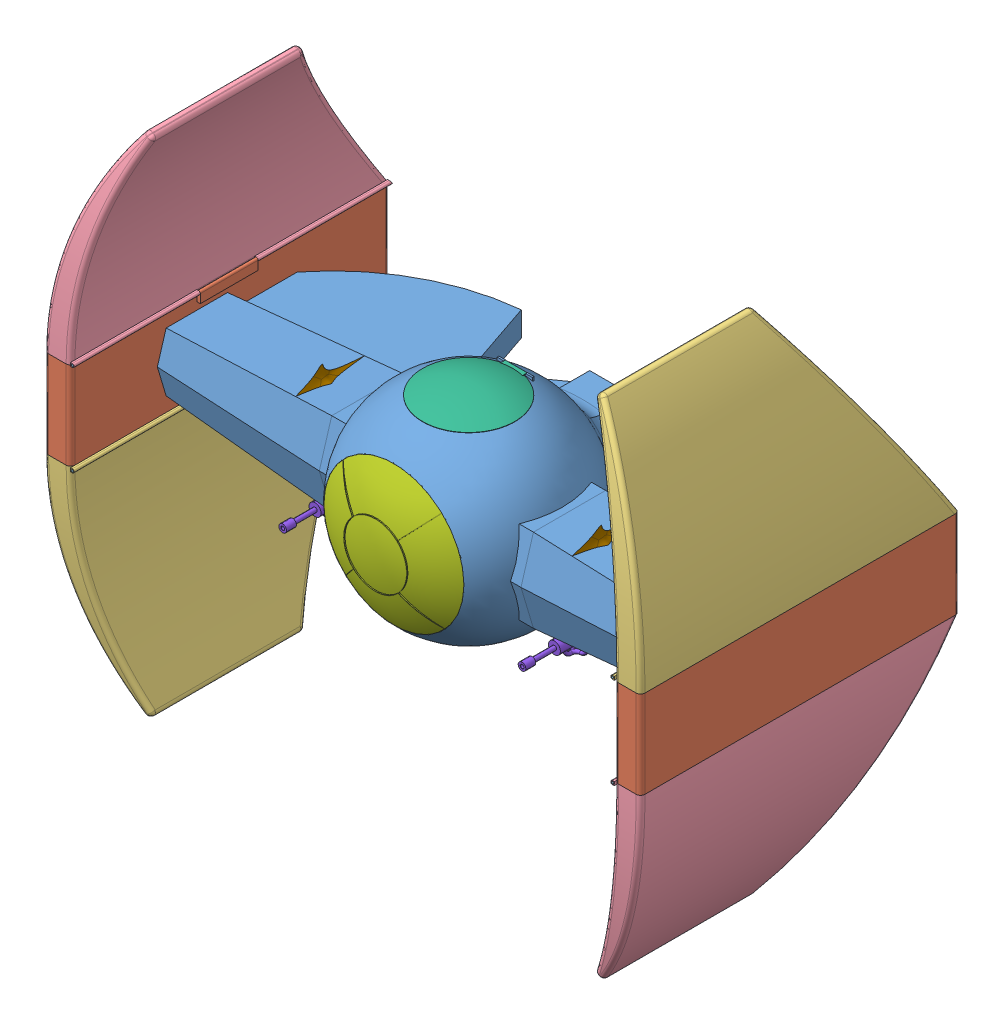
SolidWorks assembly Tie Advanced-I Assembly, configuration Default. Lengths in mm.
Overall size (35.64 28.86 19.17).
19 component instances, 9 part files, 24 mates.
Components (placement in the parent):
- Central Hub-1: Central Hub [Default] at (12.8467 16.2604 27.8507) size (32.2 11.15 14.52)
- Wing Subassembly-1: Wing Subassembly [Default] at (21.8643 7.0136 11.8834) size (6.34 28.86 19.17) (flexible)
  - Tie Wing Attachment-1: Tie Wing Attachment [Default] at (6.4824 6.7469 4.9672) size (2.1 5.4 18.2)
  - Tie Wing 1-1: Tie Wing 1 [Default] at (6.4826 11.7469 23.1672) size (6.34 11.93 19.16)
  - Tie Wing 2-1: Tie Wing 2 [Default] at (6.4824 6.7469 4.9672) x (1 0 0) z (0 0 -1) size (6.29 11.93 19.17)
  - Wing Attachment Rod-1: Wing Attachment Rod [Default] at (6.3824 11.8469 5.1672) x (0 0 1) z (-0.451392 -0.892326 0) size (18 0.12 0.12)
  - Wing Attachment Rod-2: Wing Attachment Rod [Default] at (6.3824 6.6469 23.1672) x (0 0 -1) z (1 0 0) size (18 0.12 0.12)
- Wing Subassembly-2: Wing Subassembly [Default] at (3.8292 25.5073 11.8834) x (-1 0 0) z (0 0 1) size (6.34 28.86 19.17) (flexible)
  - Tie Wing Attachment-1: Tie Wing Attachment [Default] at (6.4824 6.7469 4.9672) size (2.1 5.4 18.2)
  - Tie Wing 1-1: Tie Wing 1 [Default] at (6.4826 11.7469 23.1672) size (6.34 11.93 19.16)
  - Tie Wing 2-1: Tie Wing 2 [Default] at (6.4824 6.7469 4.9672) x (1 0 0) z (0 0 -1) size (6.29 11.93 19.17)
  - Wing Attachment Rod-1: Wing Attachment Rod [Default] at (6.3824 11.8469 5.1672) x (0 0 1) z (-0.451392 -0.892326 0) size (18 0.12 0.12)
  - Wing Attachment Rod-2: Wing Attachment Rod [Default] at (6.3824 6.6469 23.1672) x (0 0 -1) z (1 0 0) size (18 0.12 0.12)
- Hatch-1: Hatch [Default] at (12.8467 21.2554 27.8507) x (0 0 -1) z (1 0 0) size (5.35 0.85 5.25)
- Window-1: Window [Default] at (12.8467 16.2604 31.6007) x (-0.032533 0.999471 0) z (0.999471 0.032533 0) size (8 1.91 8)
- Cannon-1: Cannon [Default] at (19.6581 13.5606 26.7075) x (0.997433 0.071611 0) z (0 0 1) size (2.7 1.35 5.03)
- Cannon-2: Cannon [Default] at (6.0354 13.5606 26.7075) x (0.997433 -0.071611 0) z (0 0 1) size (2.7 1.35 5.03)
- TieFin-1: TieFin [Default] at (20.7443 18.4644 28.2031) x (-0.011968 0.000859 0.999928) z (-0.997361 0.071605 -0.011999) size (3.98 0.83 0.95)
- TieFin-2: TieFin [Default] at (4.949 18.4644 28.2031) x (0.011968 0.000859 0.999928) z (-0.997361 -0.071605 0.011999) size (3.98 0.83 0.95)
Mates (geometry in assembly coordinates):
- Coincident1: coincident anti-aligned: plane of Central Hub-1 through (28.9467 16.2604 27.8507) normal (1 0 0); plane of Wing Subassembly-1/Tie Wing Attachment-1 through (28.9467 13.7604 16.8507) normal (-1 0 0)
- Concentric1: concentric aligned: circle of Central Hub-1; circle of Wing Subassembly-1/Tie Wing Attachment-1
- Concentric2: concentric aligned: circle of Central Hub-1; circle of Wing Subassembly-2/Tie Wing Attachment-1
- Coincident3: coincident anti-aligned: plane of Central Hub-1 through (-3.2533 16.2604 27.8507) normal (-1 0 0); plane of Wing Subassembly-2/Tie Wing Attachment-1 through (-3.2533 18.7604 16.8507) normal (1 0 0)
- Coincident4: coincident anti-aligned: plane of Central Hub-1 through (-3.2533 15.9604 22.7507) normal (0 -1 0); plane of Wing Subassembly-2/Tie Wing Attachment-1 through (-3.2533 15.9604 26.3507) normal (0 1 0)
- Coincident5: coincident anti-aligned: plane of Central Hub-1 through (28.9467 16.5604 26.3507) normal (0 1 0); plane of Wing Subassembly-1/Tie Wing Attachment-1 through (28.9467 16.5604 26.3507) normal (0 -1 0)
- Concentric3: concentric aligned: cylinder of Central Hub-1 through (12.8467 16.2604 33.8507) axis (0 0 -1) radius 4; cylinder of Window-1 through (12.8467 16.2604 32.1007) axis (0 0 -1) radius 4
- Coincident6: coincident aligned: circle of Central Hub-1; circle of Window-1
- Coincident7: coincident anti-aligned: plane of Central Hub-1 through (13.0459 13.4869 27.8507) normal (0.071611 -0.997433 0); plane of Cannon-1 through (18.8315 13.9023 36.7075) normal (-0.071611 0.997433 0)
- Coincident9: coincident anti-aligned: plane of Central Hub-1 through (12.6476 13.4869 27.8507) normal (-0.071611 -0.997433 0); circle of Cannon-2
- Coincident11: coincident aligned: plane of Cannon-1 through (19.6698 13.3966 31.6319) normal (0 0 1); plane of Cannon-2 through (6.0237 13.3966 31.6319) normal (0 0 1)
- Coincident13: coincident aligned: plane of Wing Subassembly-1/Tie Wing Attachment-1 through (28.1467 13.6604 27.8507) normal (0 0 1); circle of Cannon-1
- Distance1: distance = 0.9 mm anti-aligned: sphere of Central Hub-1; sphere of Cannon-1
- Distance2: distance = 0.9 mm anti-aligned: sphere of Central Hub-1; sphere of Cannon-2
- Coincident14: coincident anti-aligned: plane of Central Hub-1 through (13.0459 19.034 27.8507) normal (0.071611 0.997433 0); plane of TieFin-1 through (20.7336 18.482 28.4649) normal (-0.071611 -0.997433 0)
- Coincident15: coincident: line of Central Hub-1 through (28.3467 17.9354 29.6007) axis (-0.996938 0.071575 0.031495); point of TieFin-1
- Coincident18: coincident: line of Central Hub-1 through (28.3467 17.9354 26.1007) axis (-0.996938 0.071575 -0.031495); point of TieFin-1
- Distance4: distance = 7.66 mm: moEndPointRef_w of TieFin-1; line of Central Hub-1 through (28.3467 17.9354 26.1007) axis (0 0 1)
- Coincident20: coincident anti-aligned: plane of Central Hub-1 through (12.6476 19.034 27.8507) normal (-0.071611 0.997433 0); plane of TieFin-2 through (4.9421 18.4808 28.4652) normal (0.071611 -0.997433 0)
- Coincident21: coincident: line of Central Hub-1 through (-2.6533 17.9354 29.6007) axis (0.996938 0.071575 0.031495); point of TieFin-2
- Coincident22: coincident: line of Central Hub-1 through (-2.6533 17.9354 26.1007) axis (0.996938 0.071575 -0.031495); point of TieFin-2
- Distance5: distance = 7.66 mm: moEndPointRef_w of TieFin-2; line of Central Hub-1 through (-2.6533 17.9354 26.1007) axis (0 0 1)
- LimitAngle4: limit planar angle = 0 rad aligned: line of Hatch-1 through (13.4717 21.5554 25.4107) axis (0 0 -1); line of Central Hub-1 through (13.8467 21.5604 25.2257) axis (0 0 -1)
- Coincident28: coincident anti-aligned: circle of Central Hub-1; circle of Hatch-1
